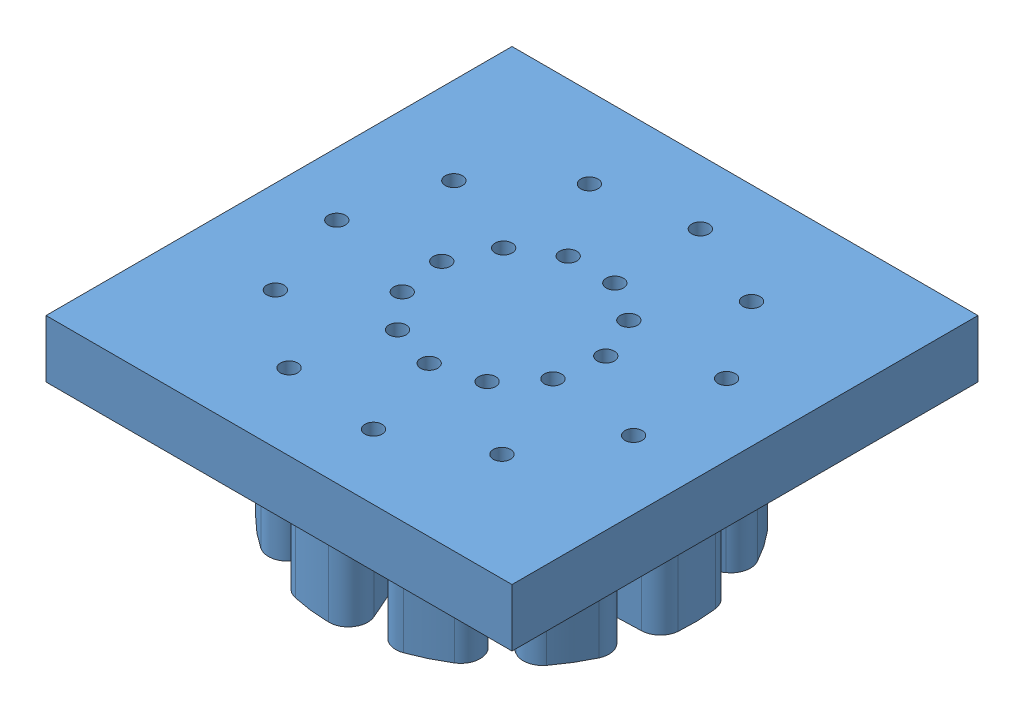
SolidWorks assembly Moldy2, configuration Default. Lengths in mm.
Overall size (36 13.6 36).
2 component instances, 2 part files, 3 mates.
Components (placement in the parent):
- COmpression Wheel v5-1: COmpression Wheel v5 [Default] at origin size (32.5 10 32.5) (hidden)
- Cavity No Cavity-1: Cavity No Cavity [Default] at (0 9.65 0) x (1 0 0) z (0 0 -1) size (36 13.6 36)
Mates (geometry in assembly coordinates):
- Coincident4: coincident aligned: plane of Cavity No Cavity-1 through (0 3.15 0) normal (0 -1 0); circle of COmpression Wheel v5-1
- Coincident2: coincident aligned: plane of COmpression Wheel v5-1 through (0 0 0) normal (1 0 0); plane of Cavity No Cavity-1 through (0 9.65 0) normal (1 0 0)
- Coincident3: coincident anti-aligned: plane of COmpression Wheel v5-1 through (0 0 0) normal (0 0 1); plane of Cavity No Cavity-1 through (0 9.65 0) normal (0 0 -1)
